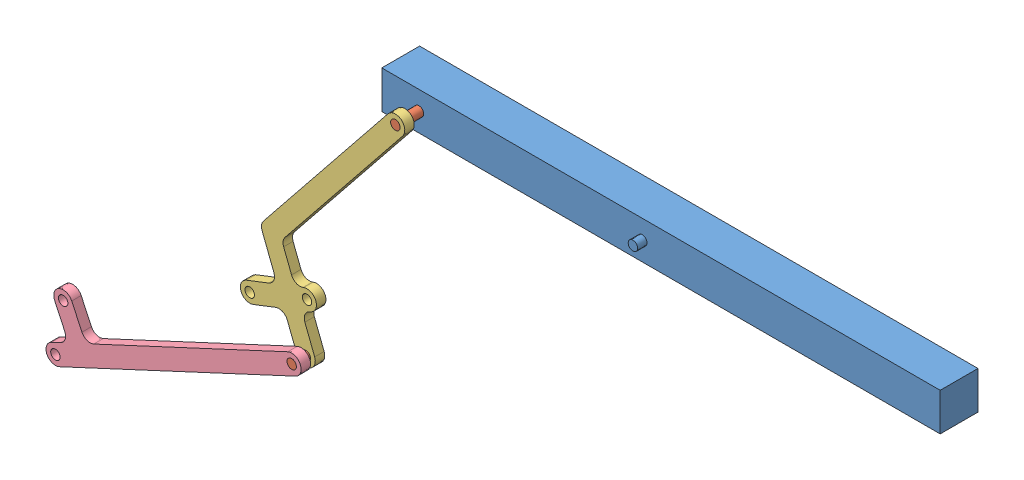
SolidWorks assembly Leg Assembly, configuration Default. Lengths in mm.
Overall size (1178.52 538.91 101.6).
5 component instances, 4 part files, 8 mates.
Components (placement in the parent):
- Mounting-1: Mounting [Default] at (-350.7024 95.8455 119.9449) size (750 50.8 63.5)
- Pin Joint-1: Pin Joint [Default] at (-306.025 43.5738 170.7449) size (12.7 12.7 31.75)
- Thigh-1: Thigh [Default] at (-340.0833 79.4749 189.7949) x (0.939214 -0.343333 0) z (0 0 1) size (110.94 375.4 12.7)
- Pin Joint-2: Pin Joint [Default] at (-487.4355 -290.6112 189.7949) x (0.229042 -0.973417 0) z (0 0 1) size (12.7 12.7 31.75)
- Shank-1: Shank [Default] at (-460.2896 -249.2354 208.8449) x (0.421902 -0.906642 0) z (0 0 1) size (82.55 375.4 12.7)
Mates (geometry in assembly coordinates):
- Concentric1: concentric aligned: cylinder of Mounting-1 through (-340.0833 79.4749 170.7449) axis (0 0 -1) radius 6.35; cylinder of Pin Joint-1 through (-340.0833 79.4749 202.4949) axis (0 0 -1) radius 6.35
- Coincident1: coincident aligned: circle of Mounting-1; circle of Pin Joint-1
- Concentric6: concentric aligned: cylinder of Pin Joint-2 through (-460.2896 -249.2354 221.5449) axis (0 0 -1) radius 6.35; cylinder of Shank-1 through (-460.2896 -249.2354 221.5449) axis (0 0 -1) radius 6.35
- Coincident7: coincident aligned: circle of Pin Joint-2; circle of Shank-1
- Concentric7: concentric aligned: cylinder of Pin Joint-1 through (-340.0833 79.4749 202.4949) axis (0 0 -1) radius 6.35; cylinder of Thigh-1 through (-340.0833 79.4749 202.4949) axis (0 0 -1) radius 6.35
- Coincident8: coincident aligned: circle of Pin Joint-1; circle of Thigh-1
- Concentric8: concentric aligned: cylinder of Thigh-1 through (-460.2896 -249.2354 202.4949) axis (0 0 -1) radius 6.35; cylinder of Pin Joint-2 through (-460.2896 -249.2354 221.5449) axis (0 0 -1) radius 6.35
- Coincident9: coincident aligned: circle of Thigh-1; circle of Pin Joint-2
